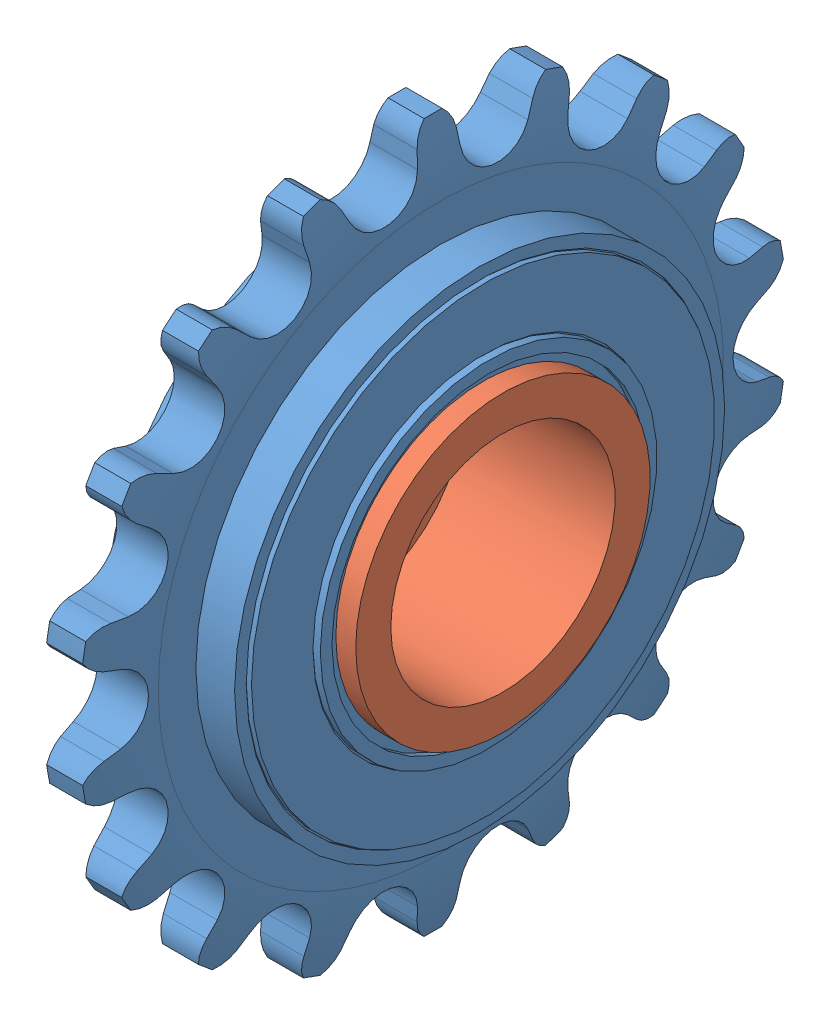
SolidWorks assembly spoket, configuration Default. Lengths in mm.
Overall size (19 78.98 78.1).
2 component instances, 2 part files, 3 mates.
Components (placement in the parent):
- Sprocket-1: Sprocket [18 teeth 420] at (-30.1316 4.2675 12.8372) size (15.78 78.98 78.1)
- spoket_joint-1: spoket_joint [Default] at (-39.3316 4.2675 12.8372) x (0 0 -1) z (1 0 0) size (40 40 19)
Mates (geometry in assembly coordinates):
- Concentric1: concentric aligned: cylinder of Sprocket-1 through (-30.1316 4.2675 12.8372) axis (-1 0 0) radius 16.4042; cylinder of spoket_joint-1 through (-20.3316 4.2675 12.8372) axis (-1 0 0) radius 16.405
- Coincident1: coincident anti-aligned: plane of Sprocket-1 through (-37.3316 23.23 12.8372) normal (-1 0 0); plane of spoket_joint-1 through (-37.3316 4.2675 12.8372) normal (1 0 0)
- Parallel1: parallel aligned: plane of spoket_joint-1 through (-39.3316 4.2675 12.8372) normal (0 1 0)
